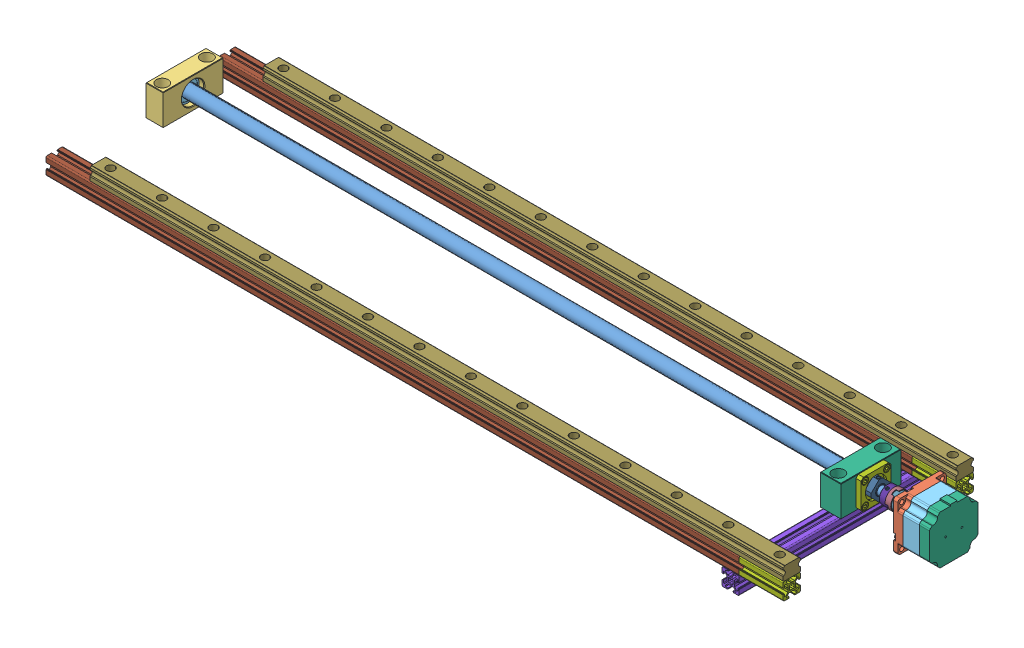
SolidWorks assembly bssc1510_835_sc8_2_14b, configuration Standard. Lengths in mm.
Overall size (906.6 67.9 221.5).
37 component instances, 26 part files, 27 mates.
Components (placement in the parent):
- x.1-1: x.1 [Standard] at (59.7765 217.2485 258.591) size (835 15 15)
- x.3-1: x.3 [Standard] at (59.7765 217.2485 258.591) size (10 15 15)
- buv12_2_14b-1: buv12_2_14b [Standard] at (57.7765 217.2485 258.591) size (20 36 70)
  - x.1.1.1-1: x.1.1.1 [Standard] at origin size (20 36 70)
  - x.2.1.1-1: x.2.1.1 [Standard] at origin size (1 16.8 14.65)
  - x.3.1.1-1: x.3.1.1 [Standard] at origin size (8 26 26)
- bsv12_2_14b-1: bsv12_2_14b [Standard] at (843.7765 217.2485 258.591) size (35.5 36 70)
  - x.1.1-1: x.1.1 [Standard] at origin size (24 36 70)
  - x.2.1-1: x.2.1 [Standard] at origin size (8 35 35)
  - x.3.1-1: x.3.1 [Standard] at origin size (16 28 28)
  - x.4.1-1: x.4.1 [Standard] at origin size (5.5 15 15)
  - x.5.1-1: x.5.1 [Standard] at origin size (8 22.84 22.84)
- bosch_3842992888_9c9s6psdorxyhd1epp1jf78yp-1: bosch_3842992888_9c9s6psdorxyhd1epp1jf78yp [Default] at (57.7765 209.2485 198.591) size (808 20 20)
- bosch_3842992888_9c9s6psdorxyhd1epp1jf78yp-2: bosch_3842992888_9c9s6psdorxyhd1epp1jf78yp [Default] at (57.7765 209.2485 400.091) size (808 20 20)
- x.1.1.1.1-1: x.1.1.1.1 [Standard] at (513.0765 219.2485 198.591) x (0 0 1) z (-1 0 0) size (20 15.5 808)
- x.1.1.1.1-2: x.1.1.1.1 [Standard] at (513.0765 219.2485 400.091) x (0 0 1) z (-1 0 0) size (20 15.5 808)
- mco20_6_35_10_2_14b_umbenant-1: mco20_6_35_10_2_14b_umbenant [Standard] at (898.0765 217.2485 258.591) x (-1 0 0) z (0 0.924225 0.381849) size (21.4 21 21)
  - x.a-1: x.a [Standard] at origin size (6.6 21 21)
  - x.b-1: x.b [Standard] at origin size (10.2 20 20)
  - x.c-1: x.c [Standard] at origin size (4 4 5.1)
  - x.d-1: x.d [Standard] at origin size (4 5.1 4)
  - x.e-1: x.e [Standard] at origin size (10.2 20 20)
  - x.f-1: x.f [Standard] at origin size (4 5.1 4)
  - x.g-1: x.g [Standard] at origin size (4 4 5.1)
- ST5918X1008-1: ST5918X1008 [Standard] at (927.0765 217.2485 258.591) x (0 0 1) z (-1 0 0) size (56.4 58.22 62.6)
  - Frontcap_ST5918_1-1: Frontcap_ST5918_1 [Standard] at (0 0 -6.3) size (56.4 56.4 12.6)
  - shaft_forward_5709_1-1: shaft_forward_5709_1 [Standard] at (0 0 25.3) x (0.985699 0.168514 0) z (0 0 -1) size (6.35 6.35 19)
  - Schrauben_ISO_7045_M3_1-1: Schrauben_ISO_7045_M3_1 [Standard] at (-11.2 -25.35 2.2) x (1 0 0) z (0 -1 0) size (5.57 2.46 5.76)
  - Schrauben_ISO_7045_M3_1-2: Schrauben_ISO_7045_M3_1 [Standard] at (25.35 -11.2 2.2) x (1 0 0) z (0 -1 0) size (5.57 2.46 5.76)
  - Schrauben_ISO_7045_M3_1-3: Schrauben_ISO_7045_M3_1 [Standard] at (11.2 25.35 2.2) x (1 0 0) z (0 -1 0) size (5.57 2.46 5.76)
  - Schrauben_ISO_7045_M3_1-4: Schrauben_ISO_7045_M3_1 [Standard] at (-25.35 11.2 2.2) x (1 0 0) z (0 -1 0) size (5.57 2.46 5.76)
  - Stator_5918_X-1: Stator_5918_X [Standard] at (0 0 -6.3) x (1 0 0) z (0 0 -1) size (56.4 56.4 19)
  - Endcap ST5918_kompl_1-1: Endcap ST5918_kompl_1 [Standard] at (0 0.85 -31.3) x (1 0 0) z (0 0 -1) size (56.4 58.1 12)
    - Endcap_5918_1-1: Endcap_5918_1 [Standard] at (0 0.85 -6) size (56.4 58.1 12)
- bosch_3842992888_7lia0498i12anehwyzh4p1fgc-1: bosch_3842992888_7lia0498i12anehwyzh4p1fgc [Default] at (917.0765 209.2485 400.091) x (-1 0 0) z (0 -1 0) size (51.3 20 20)
- bosch_3842992888_7lia0498i12anehwyzh4p1fgc-2: bosch_3842992888_7lia0498i12anehwyzh4p1fgc [Default] at (865.7765 209.2485 198.591) size (51.3 20 20)
- bosch_3842992888_dva00vq3akj3v9a29cw93lqum-2: bosch_3842992888_dva00vq3akj3v9a29cw93lqum [Default] at (855.7765 189.2485 188.591) x (0 0 1) z (-1 0 0) size (221.5 20 20)
Mates (geometry in assembly coordinates):
- Konzentrisch2: concentric aligned: cylinder of x.1-1 through (859.6765 217.2485 258.591) axis (1 0 0) radius 6; cylinder of x.3-1 through (844.7765 217.2485 258.591) axis (1 0 0) radius 6
- Deckungsgleich1: coincident anti-aligned: plane of x.1-1 through (839.7765 224.1485 258.591) normal (1 0 0); plane of x.3-1 through (839.7765 224.1485 258.591) normal (-1 0 0)
- Konzentrisch3: concentric anti-aligned: cylinder of x.1-1 through (67.6265 217.2485 258.591) axis (1 0 0) radius 5; cylinder of buv12_2_14b-1/x.3.1.1-1 through (67.7765 217.2485 258.591) axis (-1 0 0) radius 5
- Deckungsgleich2: coincident anti-aligned: plane of x.1-1 through (71.7765 223.3985 258.591) normal (-1 0 0); plane of buv12_2_14b-1/x.3.1.1-1 through (71.7765 211.1235 258.591) normal (1 0 0)
- Konzentrisch4: concentric anti-aligned: cylinder of x.1-1 through (859.6765 217.2485 258.591) axis (1 0 0) radius 6; cylinder of bsv12_2_14b-1/x.3.1-1 through (853.7015 217.2485 258.591) axis (-1 0 0) radius 6
- Deckungsgleich4: coincident anti-aligned: plane of x.3-1 through (849.7765 224.1485 258.591) normal (1 0 0); plane of bsv12_2_14b-1/x.3.1-1 through (849.7765 210.2985 258.591) normal (-1 0 0)
- Deckungsgleich20: coincident anti-aligned: plane of bosch_3842992888_9c9s6psdorxyhd1epp1jf78yp-1 through (57.7765 219.2485 207.091) normal (0 1 0); plane of x.1.1.1.1-1 through (109.0765 219.2485 189.191) normal (0 -1 0)
- Deckungsgleich21: coincident aligned: plane of bosch_3842992888_9c9s6psdorxyhd1epp1jf78yp-1 through (57.7765 212.7485 208.591) normal (0 0 1); plane of x.1.1.1.1-1 through (109.0765 219.8485 208.591) normal (0 0 1)
- Deckungsgleich23: coincident anti-aligned: plane of bosch_3842992888_9c9s6psdorxyhd1epp1jf78yp-2 through (57.7765 219.2485 396.591) normal (0 1 0); plane of x.1.1.1.1-2 through (109.0765 219.2485 390.691) normal (0 -1 0)
- Deckungsgleich24: coincident aligned: plane of bosch_3842992888_9c9s6psdorxyhd1epp1jf78yp-2 through (57.7765 217.7485 390.091) normal (0 0 -1); plane of x.1.1.1.1-2 through (109.0765 224.3485 390.091) normal (0 0 -1)
- Konzentrisch6: concentric aligned: cylinder of x.1-1 through (887.0265 217.2485 258.591) axis (1 0 0) radius 5; cylinder of mco20_6_35_10_2_14b_umbenant-1/x.e-1 through (892.4765 217.2485 258.591) axis (1 0 0) radius 5
- Deckungsgleich34: coincident anti-aligned: plane of x.1-1 through (894.7765 219.4985 258.591) normal (1 0 0); plane of mco20_6_35_10_2_14b_umbenant-1/x.a-1 through (894.7765 210.5017 255.8035) normal (-1 0 0)
- Konzentrisch7: concentric anti-aligned: cylinder of mco20_6_35_10_2_14b_umbenant-1/x.b-1 through (903.6765 217.2485 258.591) axis (-1 0 0) radius 3.175; cylinder of ST5918X1008-1/shaft_forward_5709_1-1 through (901.7765 217.2485 258.591) axis (1 0 0) radius 3.175
- Deckungsgleich35: coincident anti-aligned: circle of mco20_6_35_10_2_14b_umbenant-1/x.b-1; plane of ST5918X1008-1/shaft_forward_5709_1-1 through (901.7765 217.2485 258.591) normal (-1 0 0)
- Abstand3: distance = 15 mm anti-aligned: plane of bsv12_2_14b-1/x.1.1-1 through (843.7765 217.2485 223.591) normal (0 0 -1); plane of bosch_3842992888_9c9s6psdorxyhd1epp1jf78yp-1 through (57.7765 212.7485 208.591) normal (0 0 1)
- Abstand4: distance = 221.5 mm anti-aligned: plane of bosch_3842992888_9c9s6psdorxyhd1epp1jf78yp-2 through (57.7765 212.7485 410.091) normal (0 0 1); plane of bosch_3842992888_9c9s6psdorxyhd1epp1jf78yp-1 through (57.7765 217.7485 188.591) normal (0 0 -1)
- Deckungsgleich47: coincident anti-aligned: plane of bosch_3842992888_9c9s6psdorxyhd1epp1jf78yp-2 through (865.7765 209.2485 400.091) normal (1 0 0); plane of bosch_3842992888_7lia0498i12anehwyzh4p1fgc-1 through (865.7765 209.2485 400.091) normal (-1 0 0)
- Deckungsgleich48: coincident aligned: plane of bosch_3842992888_9c9s6psdorxyhd1epp1jf78yp-2 through (57.7765 212.7485 410.091) normal (0 0 1); plane of bosch_3842992888_7lia0498i12anehwyzh4p1fgc-1 through (917.0765 217.7485 410.091) normal (0 0 1)
- Deckungsgleich49: coincident aligned: plane of bosch_3842992888_9c9s6psdorxyhd1epp1jf78yp-2 through (57.7765 199.2485 403.591) normal (0 -1 0); plane of bosch_3842992888_7lia0498i12anehwyzh4p1fgc-1 through (917.0765 199.2485 408.591) normal (0 -1 0)
- Deckungsgleich50: coincident anti-aligned: plane of bosch_3842992888_9c9s6psdorxyhd1epp1jf78yp-1 through (865.7765 209.2485 198.591) normal (1 0 0); plane of bosch_3842992888_7lia0498i12anehwyzh4p1fgc-2 through (865.7765 209.2485 198.591) normal (-1 0 0)
- Deckungsgleich52: coincident anti-aligned: plane of bosch_3842992888_9c9s6psdorxyhd1epp1jf78yp-1 through (865.7765 209.2485 198.591) normal (1 0 0); plane of bosch_3842992888_7lia0498i12anehwyzh4p1fgc-2 through (865.7765 209.2485 198.591) normal (-1 0 0)
- Deckungsgleich53: coincident aligned: plane of bosch_3842992888_9c9s6psdorxyhd1epp1jf78yp-1 through (57.7765 217.7485 188.591) normal (0 0 -1); plane of bosch_3842992888_7lia0498i12anehwyzh4p1fgc-2 through (865.7765 217.7485 188.591) normal (0 0 -1)
- Deckungsgleich57: coincident aligned: plane of bosch_3842992888_9c9s6psdorxyhd1epp1jf78yp-2 through (57.7765 212.7485 410.091) normal (0 0 1); plane of bosch_3842992888_dva00vq3akj3v9a29cw93lqum-2 through (855.7765 189.2485 410.091) normal (0 0 1)
- Deckungsgleich58: coincident anti-aligned: plane of bosch_3842992888_7lia0498i12anehwyzh4p1fgc-1 through (917.0765 199.2485 408.591) normal (0 -1 0); plane of bosch_3842992888_dva00vq3akj3v9a29cw93lqum-2 through (847.2765 199.2485 188.591) normal (0 1 0)
- Abstand5: distance = 2 mm aligned: plane of bosch_3842992888_dva00vq3akj3v9a29cw93lqum-2 through (865.7765 197.7485 188.591) normal (1 0 0); plane of bsv12_2_14b-1/x.1.1-1 through (867.7765 199.7485 293.591) normal (1 0 0)
- Deckungsgleich63: coincident aligned: plane of x.1.1.1.1-2 through (917.0765 219.2485 400.091) normal (1 0 0); plane of bosch_3842992888_7lia0498i12anehwyzh4p1fgc-1 through (917.0765 209.2485 400.091) normal (1 0 0)
- Deckungsgleich64: coincident aligned: plane of x.1.1.1.1-1 through (917.0765 219.2485 198.591) normal (1 0 0); plane of bosch_3842992888_7lia0498i12anehwyzh4p1fgc-2 through (917.0765 209.2485 198.591) normal (1 0 0)
